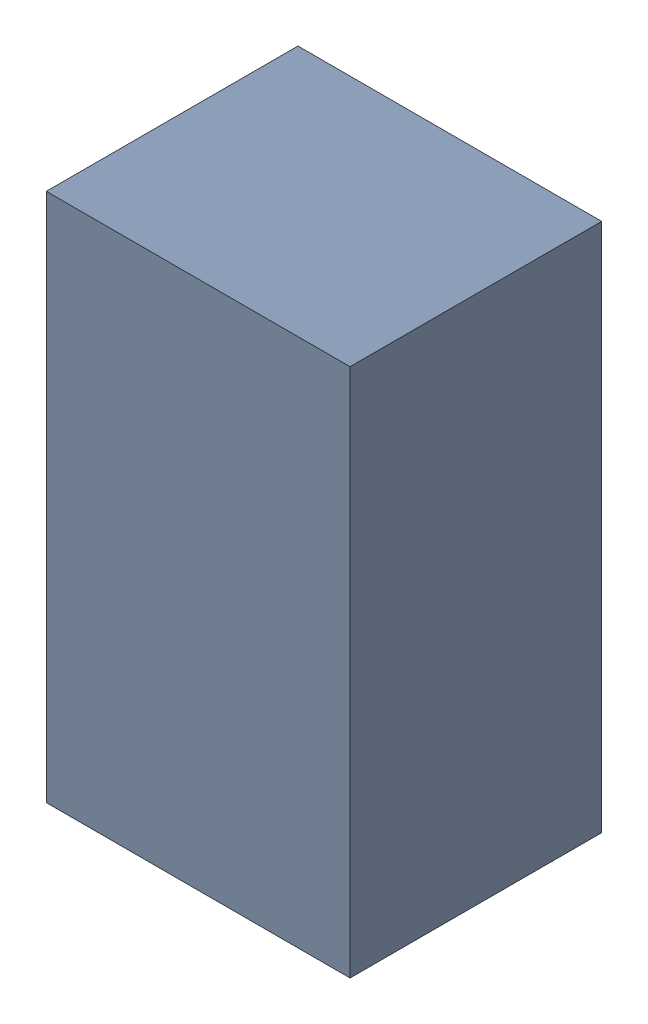
SolidWorks assembly U408PCB, configuration Default. Lengths in mm.
Overall size (1.75 3.05 1.45).
2 component instances, 1 part files, 0 mates.
Components (placement in the parent):
- 846483696-1: 846483696 [Default] at (117.3 112.7 -3.1138) size (1.75 3.05 1.45)
  - Extruded_16-1: Extruded_16 [Default] at origin size (1.75 3.05 1.45)
